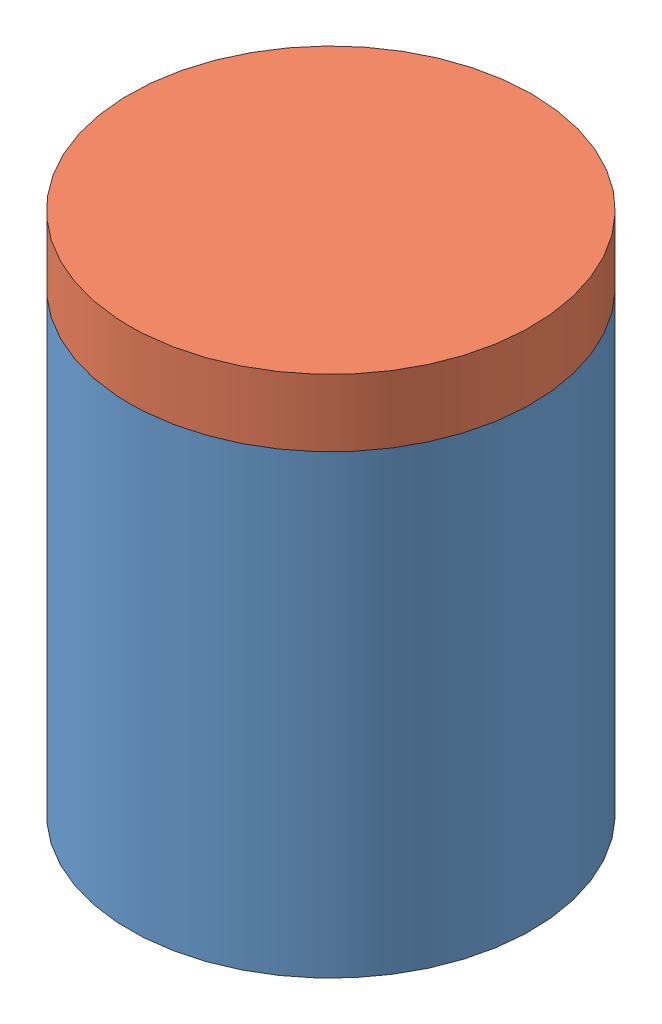
SolidWorks assembly Ensamblaje1, configuration Predeterminado. Lengths in mm.
Overall size (90 117 90).
2 component instances, 2 part files, 2 mates.
Components (placement in the parent):
- vaso 8 onzaz Bio molde-1: vaso 8 onzaz Bio molde [Predeterminado] at (-2.7501 -23.3425 0) size (90 102 90)
- vaso 8 onzaz Bio molde 2.1-1: vaso 8 onzaz Bio molde 2.1 [Predeterminado] at (-2.7501 -23.3425 0) size (90 101 90)
Mates (geometry in assembly coordinates):
- Concéntrica1: concentric: circle of ?; circle of ?
- Coincidente1: coincident: plane of ? through (-2.7501 64.6575 0) normal (0 1 0); plane of ? through (-2.7501 64.6575 0) normal (0 -1 0)
